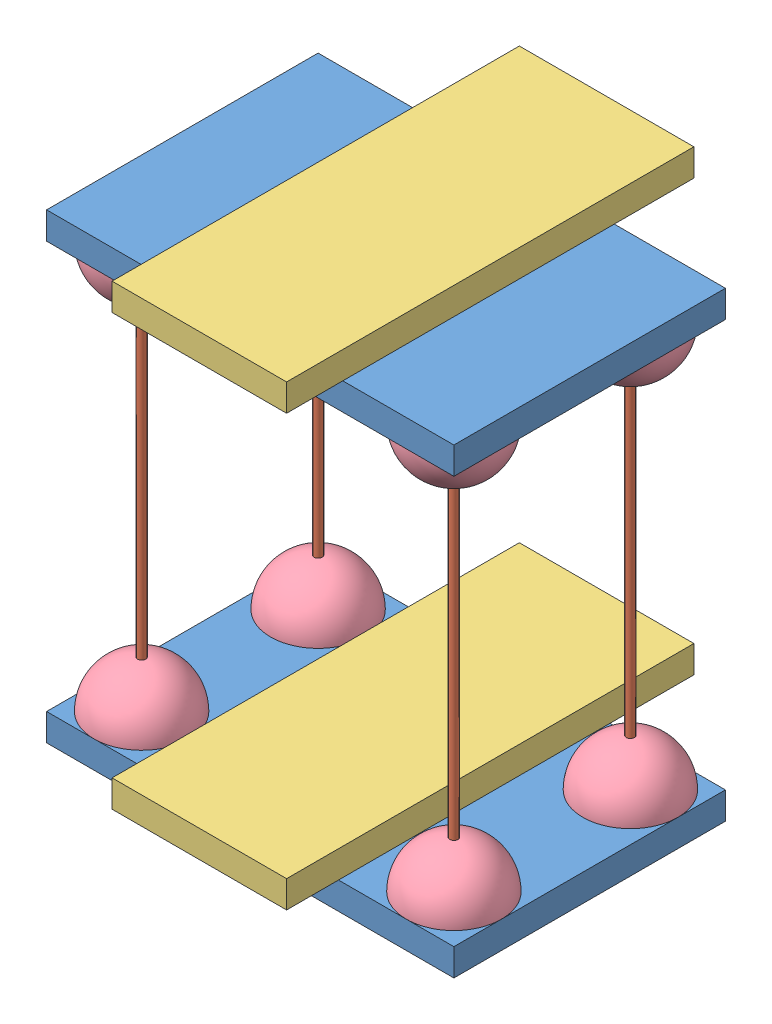
SolidWorks assembly modèle rebondissante, configuration Défaut. Lengths in mm.
Overall size (163.44 180 151.58).
17 component instances, 4 part files, 39 mates.
Components (placement in the parent):
- base-1: base [Défaut] at (-74.3534 -8.152 150) size (150 10 100)
- pic a brochette-1: pic a brochette [Défaut] at (58.1466 1.848 132.5) size (3 150 3)
- téléphone-1: téléphone [Défaut] at (-31.1278 1.848 19.1127) x (0 0 1) z (-1 0 0) size (150 10 64.29)
- base-2: base [Défaut] at (-74.3534 151.848 150) size (150 10 100)
- balle rebondissante-1: balle rebondissante [Défaut] at (58.1466 1.848 132.5) size (35 17.44 35)
- balle rebondissante-2: balle rebondissante [Défaut] at (58.1466 151.848 132.5) x (-0.837169 0 -0.546944) z (-0.546944 0 0.837169) size (35 17.44 35)
- balle rebondissante-3: balle rebondissante [Défaut] at (58.1466 1.848 67.5) size (35 17.44 35)
- balle rebondissante-4: balle rebondissante [Défaut] at (-56.8534 1.848 67.5) size (35 17.44 35)
- balle rebondissante-5: balle rebondissante [Défaut] at (-56.8534 151.848 67.5) x (-0.837169 0 -0.546944) z (-0.546944 0 0.837169) size (35 17.44 35)
- balle rebondissante-6: balle rebondissante [Défaut] at (58.1466 151.848 67.5) x (-0.837169 0 -0.546944) z (-0.546944 0 0.837169) size (35 17.44 35)
- balle rebondissante-7: balle rebondissante [Défaut] at (-56.8534 1.848 132.5) size (35 17.44 35)
- balle rebondissante-8: balle rebondissante [Défaut] at (-56.8534 151.848 132.5) x (-0.837169 0 -0.546944) z (-0.546944 0 0.837169) size (35 17.44 35)
- pic a brochette-2: pic a brochette [Défaut] at (58.1466 1.848 67.5) size (3 150 3)
- pic a brochette-3: pic a brochette [Défaut] at (-56.8534 1.848 132.5) size (3 150 3)
- pic a brochette-4: pic a brochette [Défaut] at (-56.8534 1.848 67.5) size (3 150 3)
- base-3: base [Défaut] at (-117.1952 -31.6189 201.5012) size (150 10 100) (suppressed, hidden)
- téléphone-2: téléphone [Défaut] at (-29.5552 161.848 20.6942) x (0 0 1) z (-1 0 0) size (150 10 64.29)
Mates (geometry in assembly coordinates):
- Coïncidente1: coincident anti-aligned: plane of base-1 through (-74.3534 1.848 150) normal (0 1 0); plane of balle rebondissante-1 through (58.1466 1.848 132.5) normal (0 -1 0)
- Coïncidente2: coincident anti-aligned: plane of base-1 through (-74.3534 1.848 150) normal (0 1 0); plane of balle rebondissante-3 through (58.1466 1.848 67.5) normal (0 -1 0)
- Coïncidente3: coincident anti-aligned: plane of base-1 through (-74.3534 1.848 150) normal (0 1 0); plane of balle rebondissante-7 through (-56.8534 1.848 132.5) normal (0 -1 0)
- Coïncidente4: coincident anti-aligned: plane of base-1 through (-74.3534 1.848 150) normal (0 1 0); plane of balle rebondissante-4 through (-56.8534 1.848 67.5) normal (0 -1 0)
- Coïncidente5: coincident anti-aligned: plane of base-2 through (-74.3534 151.848 150) normal (0 -1 0); plane of balle rebondissante-6 through (58.1466 151.848 67.5) normal (0 1 0)
- Coïncidente6: coincident anti-aligned: plane of base-2 through (-74.3534 151.848 150) normal (0 -1 0); plane of balle rebondissante-5 through (-56.8534 151.848 67.5) normal (0 1 0)
- Coïncidente7: coincident anti-aligned: plane of base-2 through (-74.3534 151.848 150) normal (0 -1 0); plane of balle rebondissante-2 through (58.1466 151.848 132.5) normal (0 1 0)
- Coaxiale1: concentric anti-aligned: cylinder of pic a brochette-1 through (58.1466 151.848 132.5) axis (0 -1 0) radius 1.5; cylinder of balle rebondissante-1 through (58.1466 19.348 132.5) axis (0 1 0) radius 1.5
- Coaxiale2: concentric anti-aligned: cylinder of balle rebondissante-3 through (58.1466 19.348 67.5) axis (0 1 0) radius 1.5; cylinder of pic a brochette-2 through (58.1466 151.848 67.5) axis (0 -1 0) radius 1.5
- Coïncidente8: coincident anti-aligned: plane of base-2 through (-74.3534 151.848 150) normal (0 -1 0); plane of balle rebondissante-8 through (-56.8534 151.848 132.5) normal (0 1 0)
- Coaxiale3: concentric anti-aligned: cylinder of balle rebondissante-7 through (-56.8534 19.348 132.5) axis (0 1 0) radius 1.5; cylinder of pic a brochette-3 through (-56.8534 151.848 132.5) axis (0 -1 0) radius 1.5
- Coaxiale4: concentric anti-aligned: cylinder of balle rebondissante-4 through (-56.8534 19.348 67.5) axis (0 1 0) radius 1.5; cylinder of pic a brochette-4 through (-56.8534 151.848 67.5) axis (0 -1 0) radius 1.5
- Coïncidente9: coincident aligned: plane of balle rebondissante-4 through (-56.8534 1.848 67.5) normal (0 -1 0); plane of pic a brochette-4 through (-56.8534 1.848 67.5) normal (0 -1 0)
- Coïncidente10: coincident aligned: plane of balle rebondissante-7 through (-56.8534 1.848 132.5) normal (0 -1 0); plane of pic a brochette-3 through (-56.8534 1.848 132.5) normal (0 -1 0)
- Coïncidente11: coincident aligned: plane of balle rebondissante-3 through (58.1466 1.848 67.5) normal (0 -1 0); plane of pic a brochette-2 through (58.1466 1.848 67.5) normal (0 -1 0)
- Coïncidente12: coincident aligned: plane of pic a brochette-1 through (58.1466 1.848 132.5) normal (0 -1 0); plane of balle rebondissante-1 through (58.1466 1.848 132.5) normal (0 -1 0)
- Tangent2: tangent aligned: plane of base-1 through (-74.3534 1.848 150) normal (-1 0 0); sphere of balle rebondissante-4
- Tangent3: tangent aligned: plane of base-1 through (-74.3534 1.848 50) normal (0 0 -1); sphere of balle rebondissante-4
- Tangent4: tangent aligned: plane of base-1 through (-74.3534 1.848 150) normal (-1 0 0); sphere of balle rebondissante-7
- Tangent5: tangent aligned: plane of base-1 through (-74.3534 1.848 150) normal (0 0 1); sphere of balle rebondissante-7
- Tangent6: tangent aligned: plane of base-1 through (75.6466 1.848 150) normal (1 0 0); sphere of balle rebondissante-1
- Tangent7: tangent aligned: plane of base-1 through (-74.3534 1.848 150) normal (0 0 1); sphere of balle rebondissante-1
- Tangent8: tangent aligned: plane of base-1 through (75.6466 1.848 150) normal (1 0 0); sphere of balle rebondissante-3
- Tangent9: tangent aligned: plane of base-1 through (-74.3534 1.848 50) normal (0 0 -1); sphere of balle rebondissante-3
- Tangent10: tangent aligned: plane of base-2 through (-74.3534 161.848 150) normal (0 0 1); sphere of balle rebondissante-8
- Tangent11: tangent aligned: plane of base-2 through (-74.3534 161.848 150) normal (-1 0 0); sphere of balle rebondissante-8
- Tangent12: tangent aligned: plane of base-2 through (-74.3534 161.848 150) normal (-1 0 0); sphere of balle rebondissante-5
- Tangent13: tangent aligned: plane of base-2 through (-74.3534 161.848 50) normal (0 0 -1); sphere of balle rebondissante-5
- Tangent14: tangent aligned: plane of base-2 through (75.6466 161.848 150) normal (1 0 0); sphere of balle rebondissante-6
- Tangent15: tangent aligned: plane of base-2 through (-74.3534 161.848 50) normal (0 0 -1); sphere of balle rebondissante-6
- Tangent16: tangent aligned: plane of base-2 through (75.6466 161.848 150) normal (1 0 0); sphere of balle rebondissante-2
- Tangent17: tangent aligned: plane of base-2 through (-74.3534 161.848 150) normal (0 0 1); sphere of balle rebondissante-2
- Coaxiale5: concentric aligned: cylinder of balle rebondissante-8 through (-56.8534 134.348 132.5) axis (0 -1 0) radius 1.5; cylinder of pic a brochette-3 through (-56.8534 151.848 132.5) axis (0 -1 0) radius 1.5
- Coïncidente14: coincident anti-aligned: plane of base-2 through (-74.3534 151.848 150) normal (0 -1 0); plane of pic a brochette-3 through (-56.8534 151.848 132.5) normal (0 1 0)
- Coaxiale6: concentric aligned: cylinder of balle rebondissante-6 through (58.1466 134.348 67.5) axis (0 -1 0) radius 1.5; cylinder of pic a brochette-2 through (58.1466 151.848 67.5) axis (0 -1 0) radius 1.5
- Coïncidente16: coincident anti-aligned: plane of base-1 through (-74.3534 1.848 150) normal (0 1 0); plane of téléphone-1 through (-31.1278 1.848 19.1127) normal (0 -1 0)
- Parallèle1: parallel aligned: plane of base-1 through (-74.3534 1.848 150) normal (0 0 1); plane of téléphone-1 through (-31.1278 11.848 169.1127) normal (0 0 1)
- Coïncidente18: coincident anti-aligned: plane of base-2 through (-74.3534 161.848 150) normal (0 1 0); plane of téléphone-2 through (-29.5552 161.848 20.6942) normal (0 -1 0)
- Parallèle2: parallel aligned: plane of base-2 through (-74.3534 161.848 150) normal (0 0 1); plane of téléphone-2 through (-29.5552 171.848 170.6942) normal (0 0 1)
